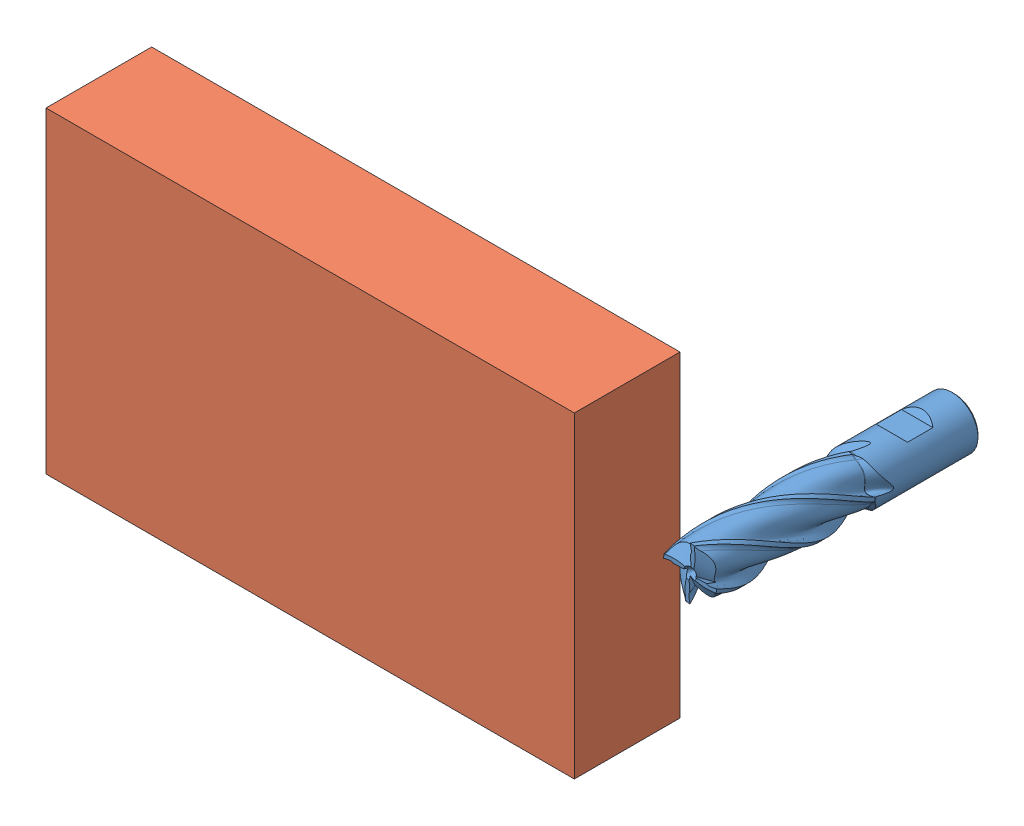
SolidWorks assembly milling_assembly, configuration 默认. Lengths in mm.
Overall size (283.88 150 162.5).
2 component instances, 2 part files, 4 mates.
Components (placement in the parent):
- endmill-1: endmill [Default] at (-7.2613 -0.9019 62.6172) size (33.25 33.25 125.23)
- workpiece-1: workpiece [默认] at (-149.5113 0 225.1172) x (1 0 0) z (0 1 0) size (250 50 150)
Mates (geometry in assembly coordinates):
- 平行1: parallel aligned: plane of endmill-1 through (-7.2613 -0.9019 62.6172) normal (0 0 -1); plane of workpiece-1 through (-159.2247 0 175.1172) normal (0 0 -1)
- 重合2: coincident aligned: plane of ? through (-159.2247 0 225.1172) normal (0 1 0)
- 距离1: distance = 10 mm anti-aligned: plane of endmill-1 through (-7.2613 -0.9019 185.1172) normal (0 0 1); plane of workpiece-1 through (-149.5113 0 175.1172) normal (0 0 -1)
- 距离2: distance = 5 mm anti-aligned: cylinder of endmill-1 through (-7.2613 -0.9019 112.6172) axis (0 0 -1) radius 12.25; plane of workpiece-1 through (-24.5113 75 175.1172) normal (1 0 0)
